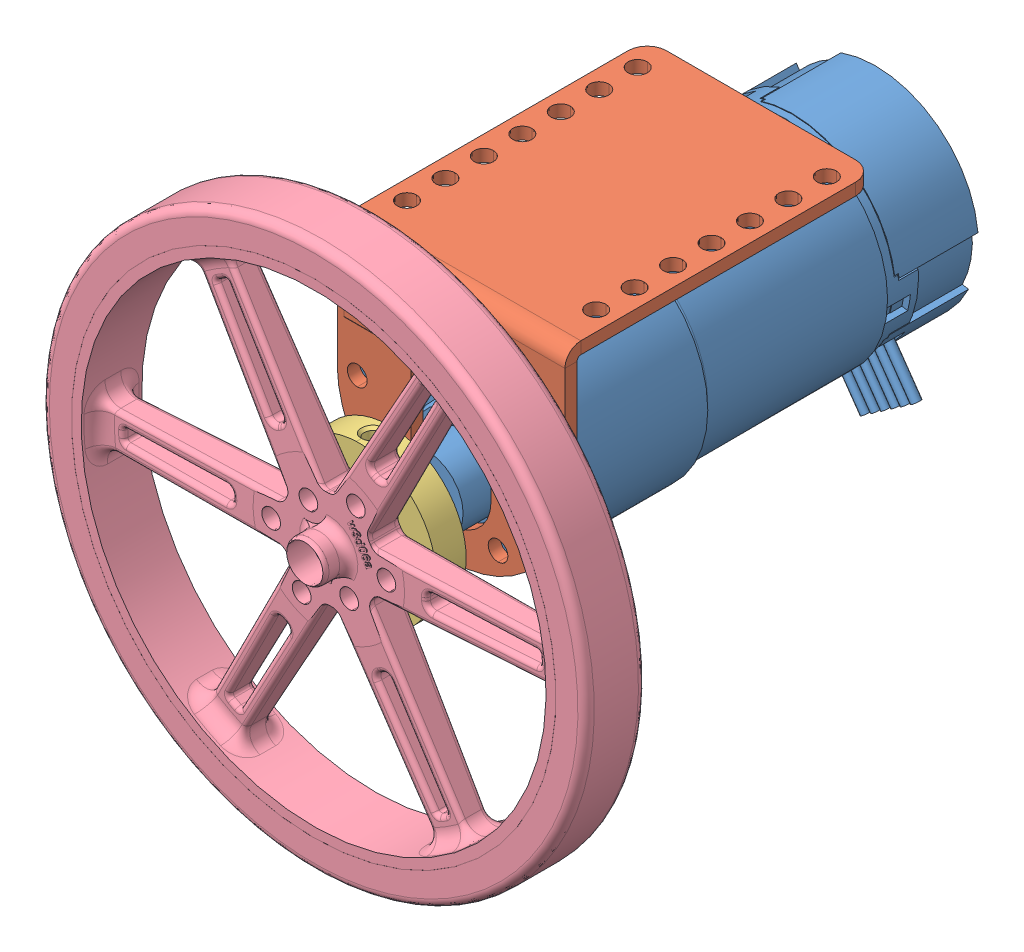
SolidWorks assembly Motor bracket hub and wheel, configuration Default. Lengths in mm.
Overall size (124.02 124.02 94.26).
4 component instances, 4 part files, 8 mates.
Components (placement in the parent):
- Motor-1: Motor [Default] at (-34.4414 -9.6533 18.8274) size (36.88 41.23 90.1)
- L bracket-1: L bracket [Default] at (-15.5164 -8.6533 32.9524) x (-1 0 0) z (0 0 1) size (37.59 39.6 51.2)
- Hub-1: Hub [Default] at (-14.5163 -16.6533 53.4524) x (-0.882948 0.469472 0) z (0 0 -1) size (25.4 25.4 9.2)
- Wheel-1: Wheel [Default] at (-14.5164 -16.6533 58.4524) x (0 0 -1) z (0.529919 -0.848048 0) size (11.46 90 90)
Mates (geometry in assembly coordinates):
- Coincident1: coincident: plane of Motor-1 through (-14.5164 -9.6533 38.7524) normal (0 0 1); plane of L bracket-1 through (-33.3124 9.1467 38.7524) normal (0 0 -1)
- Concentric1: concentric: circle of Motor-1; circle of L bracket-1
- Concentric2: concentric: circle of Motor-1; circle of L bracket-1
- Distance2: distance = 2 mm: plane of Hub-1 through (-14.5164 -16.6533 46.7524) normal (0 0 -1); plane of Motor-1 through (-14.5164 -9.6533 44.7524) normal (0 0 1)
- Concentric5: concentric: circle of Motor-1; circle of Hub-1
- Concentric6: concentric: circle of Motor-1; circle of Wheel-1
- Concentric7: concentric: circle of Hub-1; circle of Wheel-1
- Coincident5: coincident: plane of Hub-1 through (-14.5164 -16.6533 55.9524) normal (0 0 1); plane of Wheel-1 through (-25.117 -23.2773 55.9524) normal (0 0 -1)
